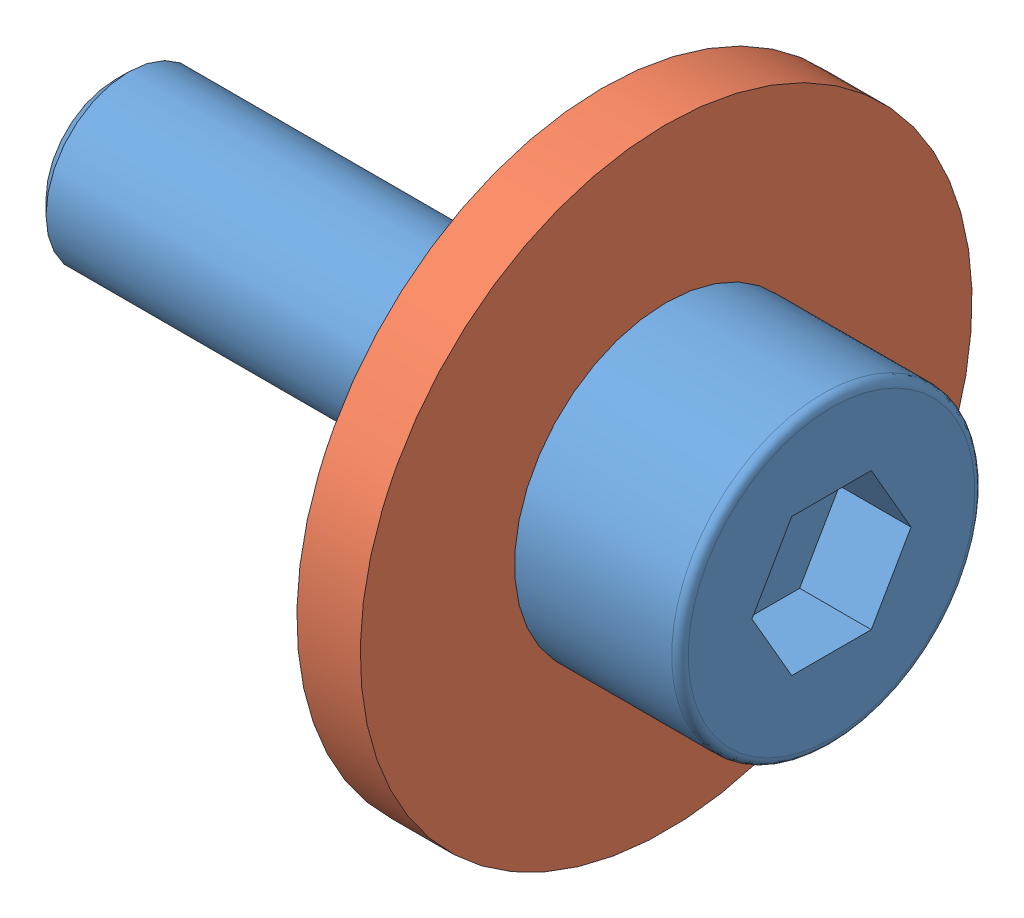
SolidWorks assembly Assembly Screw DIN 912 - M3 x 10 --- 10N + Washer NNN XXXX - M3, configuration Valor predeterminado. Lengths in mm.
Overall size (13 14.77 14.77).
2 component instances, 2 part files, 2 mates.
Components (placement in the parent):
- Screw DIN 912 - M3 x 10 --- 10N-1: Screw DIN 912 - M3 x 10 --- 10N [Valor predeterminado] at (6.1734 -0.7946 13) size (13 5.5 5.5)
- Washer NNN XXXX - M3-1: Washer NNN XXXX - M3 [Valor predeterminado] at (3.1734 -0.7946 13) x (0 0.425547 0.904937) z (-1 0 0) size (11.1 11.1 1.15)
Mates (geometry in assembly coordinates):
- Concêntrico1: concentric: cylinder of assembly; cylinder of assembly; cylinder of Screw DIN 912 - M3 x 10 --- 10N-1 through (6.1734 -0.7946 13) axis (1 0 0) radius 1.5; cylinder of Washer NNN XXXX - M3-1 through (2.0234 -0.7946 13) axis (1 0 0) radius 1.55
- Coincidente1: coincident: plane of assembly; plane of assembly; plane of Screw DIN 912 - M3 x 10 --- 10N-1 through (3.1734 1.9554 13) normal (-1 0 0); plane of Washer NNN XXXX - M3-1 through (3.1734 -0.7946 13) normal (1 0 0)
